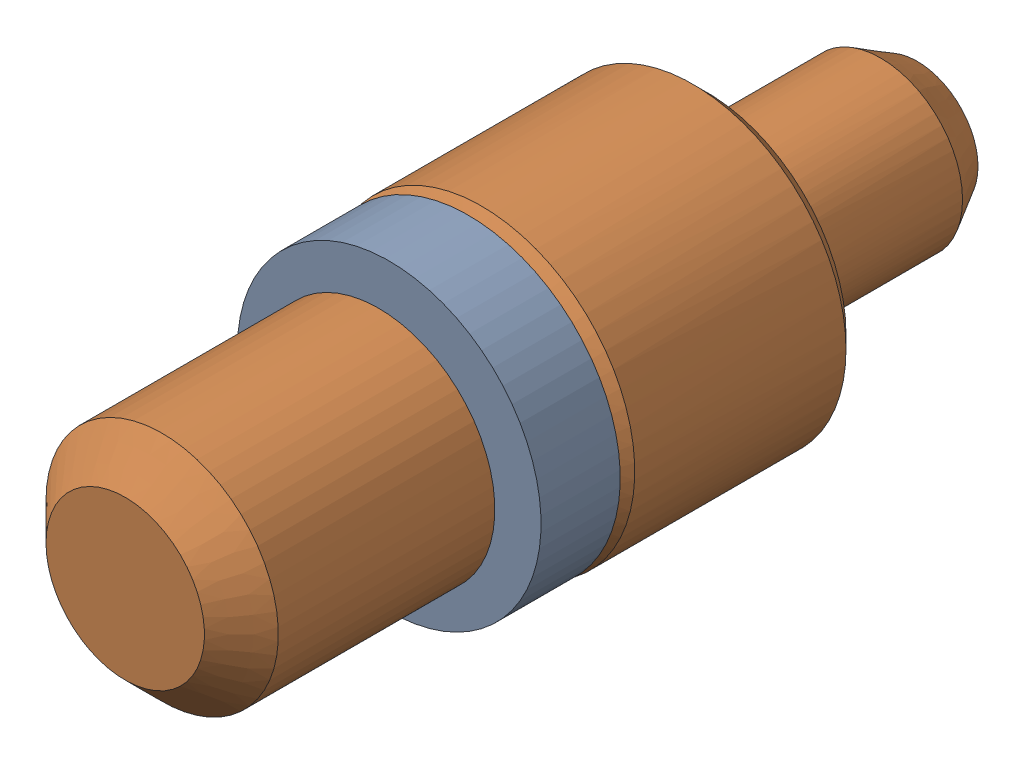
SolidWorks assembly Pogo Pin Asmbly_3, configuration Default. Lengths in mm.
Overall size (2.95 2.95 7.62).
2 component instances, 2 part files, 0 mates.
Components (placement in the parent):
- Pogo O-Ring-1: Pogo O-Ring [Default] at (69.643 62.1859 -6.223) size (2.92 2.92 0.76)
- Pogo Contact Pin-1: Pogo Contact Pin [Default] at (69.643 62.1859 -6.223) size (2.95 2.95 7.62)
